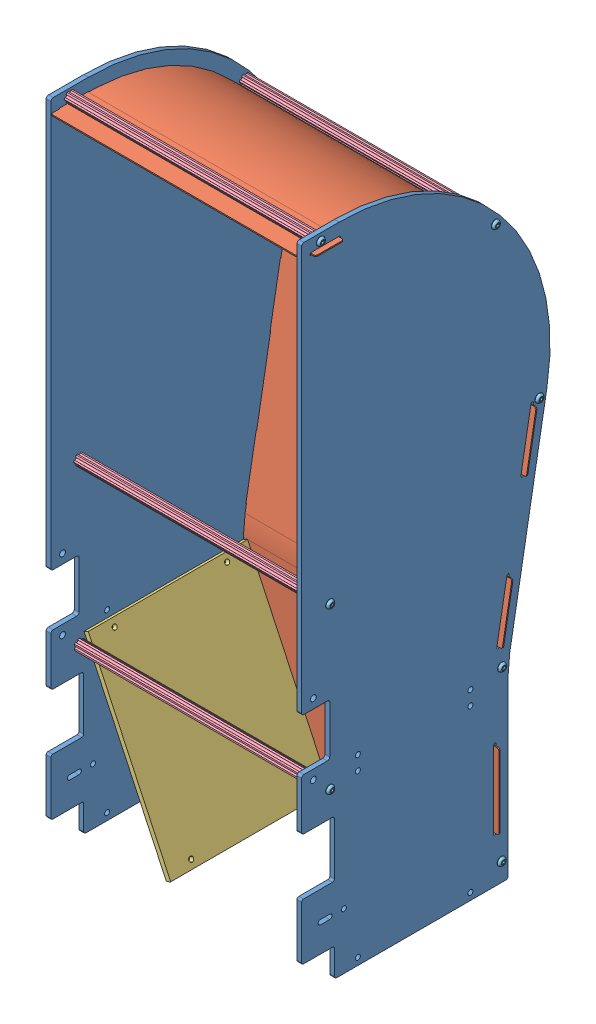
SolidWorks assembly GE-20337, configuration Default. Lengths in mm.
Overall size (358.78 884.8 336.55).
25 component instances, 5 part files, 61 mates.
Components (placement in the parent):
- GE-20333-1: GE-20333 [Default] at (-173.0375 865.7507 0) size (6.35 884.8 336.55)
- GE-20333-2: GE-20333 [Default] at (166.6875 865.7507 0) size (6.35 884.8 336.55)
- GE-20334-1: GE-20334 [Default] at (-166.6875 867.3382 0) size (358.78 867.33 319.09)
- GE-20336-1: GE-20336 [Default] at (-54.9599 0 -44.8739) x (0 0 -1) z (1 0 0) size (215.9 240.54 117.47)
- GE-20335-1: GE-20335 [Default] at (138.1125 225.8358 -38.1) x (0 -0.5 0.866025) z (-1 0 0) size (14.66 12.7 333.38)
- GE-20335-2: GE-20335 [Default] at (138.1125 25.4 -270.2993) x (0 0 1) z (-1 0 0) size (14.66 12.7 333.38)
- GE-20335-3: GE-20335 [Default] at (138.1125 875.2757 -25.4) x (0 0 1) z (-1 0 0) size (14.66 12.7 333.38)
- GE-20335-4: GE-20335 [Default] at (-138.1125 776.6047 -262.4006) x (0 -0.924225 -0.381849) z (1 0 0) size (14.66 12.7 333.38)
- GE-20335-5: GE-20335 [Default] at (-138.1125 543.2678 -321.4502) x (0 -0.924225 -0.381849) z (1 0 0) size (14.66 12.7 333.38)
- GE-20335-6: GE-20335 [Default] at (138.1125 253.1287 -270.849) x (0 0 1) z (-1 0 0) size (14.66 12.7 333.38)
- GE-20335-7: GE-20335 [Default] at (138.1125 443.4757 -38.1) x (0 0 1) z (-1 0 0) size (14.66 12.7 333.38)
- round_hex_.25_20_.625_full-28: round_hex_.25_20_.625_full [91255A539] at (176.3903 875.2757 -25.4) x (0 0 -1) z (1 0 0) size (11.1 11.1 19.46)
- round_hex_.25_20_.625_full-29: round_hex_.25_20_.625_full [91255A539] at (176.3903 776.6047 -262.4006) x (0 0.158553 -0.987351) z (1 0 0) size (11.1 11.1 19.46)
- round_hex_.25_20_.625_full-31: round_hex_.25_20_.625_full [91255A539] at (176.3903 543.2678 -321.4502) x (0 0.282984 -0.959125) z (1 0 0) size (11.1 11.1 19.46)
- round_hex_.25_20_.625_full-33: round_hex_.25_20_.625_full [91255A539] at (176.3903 443.4757 -38.1) x (0 0.371154 -0.928571) z (1 0 0) size (11.1 11.1 19.46)
- round_hex_.25_20_.625_full-35: round_hex_.25_20_.625_full [91255A539] at (176.3903 225.8358 -38.1) x (0 0.421154 -0.906989) z (1 0 0) size (11.1 11.1 19.46)
- round_hex_.25_20_.625_full-37: round_hex_.25_20_.625_full [91255A539] at (176.3903 253.1287 -270.849) x (0 0.429957 -0.902849) z (1 0 0) size (11.1 11.1 19.46)
- round_hex_.25_20_.625_full-39: round_hex_.25_20_.625_full [91255A539] at (176.3903 25.4 -270.2993) x (0 0.39282 -0.919615) z (1 0 0) size (11.1 11.1 19.46)
- round_hex_.25_20_.625_full-41: round_hex_.25_20_.625_full [91255A539] at (-176.3903 875.2757 -25.4) x (0 0.305088 0.952324) z (-1 0 0) size (11.1 11.1 19.46)
- round_hex_.25_20_.625_full-43: round_hex_.25_20_.625_full [91255A539] at (-176.3903 776.6047 -262.4006) x (0 0.168526 0.985697) z (-1 0 0) size (11.1 11.1 19.46)
- round_hex_.25_20_.625_full-45: round_hex_.25_20_.625_full [91255A539] at (-176.3903 543.2678 -321.4502) x (0 0 1) z (-1 0 0) size (11.1 11.1 19.46)
- round_hex_.25_20_.625_full-47: round_hex_.25_20_.625_full [91255A539] at (-176.3903 443.4757 -38.1) x (0 -0.168526 0.985697) z (-1 0 0) size (11.1 11.1 19.46)
- round_hex_.25_20_.625_full-49: round_hex_.25_20_.625_full [91255A539] at (-176.3903 253.1287 -270.849) x (0 -0.305088 0.952324) z (-1 0 0) size (11.1 11.1 19.46)
- round_hex_.25_20_.625_full-51: round_hex_.25_20_.625_full [91255A539] at (-176.3903 225.8358 -38.1) x (0 -0.39282 0.919615) z (-1 0 0) size (11.1 11.1 19.46)
- round_hex_.25_20_.625_full-53: round_hex_.25_20_.625_full [91255A539] at (-176.3903 25.4 -270.2993) x (0 -0.429957 0.902849) z (-1 0 0) size (11.1 11.1 19.46)
Mates (geometry in assembly coordinates):
- Coincident1: coincident aligned: plane of GE-20333-1 through (-166.6875 884.8007 0) normal (0 0 1); plane of inner_backArc-1 through (-166.6875 865.7507 0) normal (0 0 1)
- Coincident2: coincident: line of GE-20333-1 through (-173.0375 865.7507 0) axis (0 0 -1); plane of inner_backArc-1 through (-166.6875 865.7507 0) normal (0 -1 0)
- Coincident3: coincident anti-aligned: plane of GE-20333-1 through (-166.6875 240.538 -414.7618) normal (1 0 0); plane of inner_backArc-1 through (-166.6875 865.7507 0) normal (-1 0 0)
- Coincident4: coincident anti-aligned: plane of GE-20333-2 through (166.6875 240.538 -414.7618) normal (-1 0 0); plane of inner_backArc-1 through (166.6875 865.7507 0) normal (1 0 0)
- Coincident5: coincident aligned: plane of GE-20333-2 through (173.0375 884.8007 0) normal (0 0 1); plane of inner_backArc-1 through (-166.6875 865.7507 0) normal (0 0 1)
- Coincident6: coincident aligned: plane of GE-20333-1 through (-166.6875 884.8007 0) normal (0 1 0); plane of GE-20333-2 through (173.0375 884.8007 0) normal (0 1 0)
- Parallel1: parallel aligned: plane of inner_interiorRamp-1 through (-54.9599 0 -44.8739) normal (0 1 0)
- Coincident10: coincident: plane of GE-20333-1 through (-166.6875 240.538 -414.7618) normal (1 0 0); line of inner_interiorRamp-1 through (-166.6875 237.8381 -260.7739) axis (0 0 1)
- Coincident11: coincident: plane of GE-20333-1 through (-166.6875 0 -44.45) normal (0 -1 0); line of inner_interiorRamp-1 through (-54.9599 0 -260.7739) axis (0 0 1)
- Coincident12: coincident anti-aligned: plane of inner_backArc-1 through (-166.6875 854.2075 -260.7739) normal (0 0 1); plane of inner_interiorRamp-1 through (-54.9599 0 -260.7739) normal (0 0 -1)
- Coincident13: coincident anti-aligned: plane of GE-20333-1 through (-166.6875 0 -44.45) normal (0 -1 0)
- Symmetric1: symmetric aligned: plane of GE-20333-1 through (-166.6875 240.538 -414.7618) normal (1 0 0); plane of GE-20333-2 through (166.6875 240.538 -414.7618) normal (-1 0 0)
- Coincident14: coincident aligned: plane of GE-20333-2 through (173.0375 884.8007 0) normal (0 0 1)
- Concentric1: concentric anti-aligned: circle of inner_wall-2; circle of inner_churro-3
- Coincident15: coincident anti-aligned: plane of GE-20333-2 through (166.6875 240.538 -414.7618) normal (-1 0 0); plane of inner_churro-3 through (166.6875 875.2757 -25.4) normal (1 0 0)
- Concentric2: concentric aligned: circle of inner_wall-2; circle of inner_churro-4
- Coincident16: coincident anti-aligned: plane of GE-20333-2 through (166.6875 240.538 -414.7618) normal (-1 0 0); plane of inner_churro-4 through (166.6875 772.7345 -267.4349) normal (1 0 0)
- Concentric3: concentric aligned: circle of inner_wall-2; circle of inner_churro-5
- Coincident17: coincident anti-aligned: plane of GE-20333-2 through (166.6875 240.538 -414.7618) normal (-1 0 0); plane of inner_churro-5 through (166.6875 539.3977 -326.4845) normal (1 0 0)
- Concentric4: concentric anti-aligned: circle of inner_wall-1; circle of inner_churro-1
- Coincident18: coincident anti-aligned: plane of GE-20333-1 through (-166.6875 240.538 -414.7618) normal (1 0 0); plane of GE-20335-1 through (-166.6875 225.8358 -31.75) normal (-1 0 0)
- Concentric5: concentric anti-aligned: circle of inner_wall-1; circle of inner_churro-7
- Coincident19: coincident anti-aligned: plane of GE-20333-1 through (-166.6875 240.538 -414.7618) normal (1 0 0); plane of inner_churro-7 through (-166.6875 446.6507 -32.6007) normal (-1 0 0)
- Concentric6: concentric anti-aligned: circle of inner_wall-1; circle of inner_churro-2
- Coincident20: coincident anti-aligned: plane of GE-20333-1 through (-166.6875 240.538 -414.7618) normal (1 0 0); plane of inner_churro-2 through (-166.6875 28.575 -264.8001) normal (-1 0 0)
- Concentric7: concentric anti-aligned: circle of inner_wall-2; circle of inner_churro-6
- Coincident21: coincident anti-aligned: plane of GE-20333-2 through (166.6875 240.538 -414.7618) normal (-1 0 0); plane of inner_churro-6 through (166.6875 253.1287 -270.849) normal (1 0 0)
- Coincident22: coincident aligned: plane of GE-20333-2 through (173.0375 191.0505 -44.45) normal (0 0 1); plane of GE-20370-1/GE-20372-1 through (173.0375 -194.945 -44.45) normal (0 0 1)
- Coincident23: coincident anti-aligned: plane of GE-20333-2 through (173.0375 0 -44.45) normal (0 -1 0); plane of GE-20370-1/GE-20372-1 through (65.0875 0 -152.4) normal (0 1 0)
- Coincident24: coincident aligned: plane of GE-20333-2 through (173.0375 240.538 -414.7618) normal (1 0 0); plane of GE-20370-1/GE-20372-1 through (173.0375 -194.945 -260.35) normal (1 0 0)
- Parallel2: parallel anti-aligned: plane of GE-20333-2 through (173.0375 260.6211 0) normal (0 0 1); plane of GE-20335-1 through (-166.6875 229.502 -44.45) normal (0 0 -1)
- Concentric8: concentric anti-aligned: cylinder of GE-20333-2 through (173.0375 875.2757 -25.4) axis (1 0 0) radius 3.3782; cylinder of hex_.25_20_.75-1 through (173.0375 875.2757 -25.4) axis (-1 0 0) radius 3.175
- Coincident25: coincident anti-aligned: plane of GE-20333-2 through (173.0375 240.538 -414.7618) normal (1 0 0); plane of hex_.25_20_.75-1 through (173.0375 871.3654 -30.4865) normal (-1 0 0)
- Concentric9: concentric anti-aligned: cylinder of GE-20333-2 through (173.0375 875.2757 -25.4) axis (1 0 0) radius 3.3782; cylinder of round_hex_.25_20_.625_full-28 through (157.1625 875.2757 -25.4) axis (-1 0 0) radius 3.175
- Coincident26: coincident anti-aligned: plane of GE-20333-2 through (173.0375 240.538 -414.7618) normal (1 0 0); plane of round_hex_.25_20_.625_full-28 through (173.0375 869.7258 -25.4) normal (-1 0 0)
- Concentric10: concentric anti-aligned: cylinder of GE-20333-2 through (173.0375 776.6047 -262.4006) axis (1 0 0) radius 3.3782; cylinder of round_hex_.25_20_.625_full-29 through (157.1625 776.6047 -262.4006) axis (-1 0 0) radius 3.175
- Coincident27: coincident anti-aligned: plane of GE-20333-2 through (173.0375 240.538 -414.7618) normal (1 0 0); plane of round_hex_.25_20_.625_full-29 through (173.0375 771.125 -263.2806) normal (-1 0 0)
- Concentric11: concentric anti-aligned: cylinder of GE-20333-2 through (173.0375 543.2678 -321.4502) axis (1 0 0) radius 3.3782; cylinder of round_hex_.25_20_.625_full-31 through (157.1625 543.2678 -321.4502) axis (-1 0 0) radius 3.175
- Coincident28: coincident anti-aligned: plane of GE-20333-2 through (173.0375 240.538 -414.7618) normal (1 0 0); plane of round_hex_.25_20_.625_full-31 through (173.0375 537.9448 -323.0207) normal (-1 0 0)
- Concentric12: concentric anti-aligned: cylinder of GE-20333-2 through (173.0375 443.4757 -38.1) axis (1 0 0) radius 3.3782; cylinder of round_hex_.25_20_.625_full-33 through (157.1625 443.4757 -38.1) axis (-1 0 0) radius 3.175
- Coincident29: coincident anti-aligned: plane of GE-20333-2 through (173.0375 240.538 -414.7618) normal (1 0 0); plane of round_hex_.25_20_.625_full-33 through (173.0375 438.3222 -40.1599) normal (-1 0 0)
- Concentric13: concentric anti-aligned: cylinder of GE-20333-2 through (173.0375 225.8358 -38.1) axis (1 0 0) radius 3.3782; cylinder of round_hex_.25_20_.625_full-35 through (157.1625 225.8358 -38.1) axis (-1 0 0) radius 3.175
- Coincident30: coincident anti-aligned: plane of GE-20333-2 through (173.0375 240.538 -414.7618) normal (1 0 0); plane of round_hex_.25_20_.625_full-35 through (173.0375 220.8021 -40.4374) normal (-1 0 0)
- Concentric14: concentric anti-aligned: cylinder of GE-20333-2 through (173.0375 253.1287 -270.849) axis (1 0 0) radius 3.3782; cylinder of round_hex_.25_20_.625_full-37 through (157.1625 253.1287 -270.849) axis (-1 0 0) radius 3.175
- Coincident31: coincident anti-aligned: plane of GE-20333-2 through (173.0375 240.538 -414.7618) normal (1 0 0); plane of round_hex_.25_20_.625_full-37 through (173.0375 248.118 -273.2353) normal (-1 0 0)
- Concentric15: concentric anti-aligned: cylinder of GE-20333-2 through (173.0375 25.4 -270.2993) axis (1 0 0) radius 3.3782; cylinder of round_hex_.25_20_.625_full-39 through (157.1625 25.4 -270.2993) axis (-1 0 0) radius 3.175
- Coincident32: coincident anti-aligned: plane of GE-20333-2 through (173.0375 240.538 -414.7618) normal (1 0 0); plane of round_hex_.25_20_.625_full-39 through (173.0375 20.2962 -272.4794) normal (-1 0 0)
- Concentric16: concentric aligned: cylinder of GE-20333-1 through (-166.6875 875.2757 -25.4) axis (1 0 0) radius 3.3782; cylinder of round_hex_.25_20_.625_full-41 through (-157.1625 875.2757 -25.4) axis (1 0 0) radius 3.175
- Coincident33: coincident anti-aligned: plane of GE-20333-1 through (-173.0375 240.538 -414.7618) normal (-1 0 0); plane of round_hex_.25_20_.625_full-41 through (-173.0375 869.9904 -23.7068) normal (1 0 0)
- Concentric17: concentric aligned: cylinder of GE-20333-1 through (-166.6875 776.6047 -262.4006) axis (1 0 0) radius 3.3782; cylinder of round_hex_.25_20_.625_full-43 through (-157.1625 776.6047 -262.4006) axis (1 0 0) radius 3.175
- Coincident34: coincident anti-aligned: plane of GE-20333-1 through (-173.0375 240.538 -414.7618) normal (-1 0 0); plane of round_hex_.25_20_.625_full-43 through (-173.0375 771.1342 -261.4653) normal (1 0 0)
- Concentric18: concentric aligned: cylinder of GE-20333-1 through (-166.6875 543.2678 -321.4502) axis (1 0 0) radius 3.3782; cylinder of round_hex_.25_20_.625_full-45 through (-157.1625 543.2678 -321.4502) axis (1 0 0) radius 3.175
- Coincident35: coincident anti-aligned: plane of GE-20333-1 through (-173.0375 240.538 -414.7618) normal (-1 0 0); plane of round_hex_.25_20_.625_full-45 through (-173.0375 537.7179 -321.4502) normal (1 0 0)
- Concentric19: concentric aligned: cylinder of GE-20333-1 through (-166.6875 443.4757 -38.1) axis (1 0 0) radius 3.3782; cylinder of round_hex_.25_20_.625_full-47 through (-157.1625 443.4757 -38.1) axis (1 0 0) radius 3.175
- Coincident36: coincident anti-aligned: plane of GE-20333-1 through (-173.0375 240.538 -414.7618) normal (-1 0 0); plane of round_hex_.25_20_.625_full-47 through (-173.0375 438.0052 -39.0353) normal (1 0 0)
- Concentric20: concentric aligned: cylinder of GE-20333-1 through (-166.6875 253.1287 -270.849) axis (1 0 0) radius 3.3782; cylinder of round_hex_.25_20_.625_full-49 through (-157.1625 253.1287 -270.849) axis (1 0 0) radius 3.175
- Coincident37: coincident anti-aligned: plane of GE-20333-1 through (-173.0375 240.538 -414.7618) normal (-1 0 0); plane of round_hex_.25_20_.625_full-49 through (-173.0375 247.8434 -272.5422) normal (1 0 0)
- Concentric21: concentric aligned: cylinder of GE-20333-1 through (-166.6875 225.8358 -38.1) axis (1 0 0) radius 3.3782; cylinder of round_hex_.25_20_.625_full-51 through (-157.1625 225.8358 -38.1) axis (1 0 0) radius 3.175
- Coincident38: coincident anti-aligned: plane of GE-20333-1 through (-173.0375 240.538 -414.7618) normal (-1 0 0); plane of round_hex_.25_20_.625_full-51 through (-173.0375 220.732 -40.2801) normal (1 0 0)
- Concentric22: concentric aligned: cylinder of GE-20333-1 through (-166.6875 25.4 -270.2993) axis (1 0 0) radius 3.3782; cylinder of round_hex_.25_20_.625_full-53 through (-157.1625 25.4 -270.2993) axis (1 0 0) radius 3.175
- Coincident39: coincident anti-aligned: plane of GE-20333-1 through (-173.0375 240.538 -414.7618) normal (-1 0 0); plane of round_hex_.25_20_.625_full-53 through (-173.0375 20.3893 -272.6855) normal (1 0 0)
